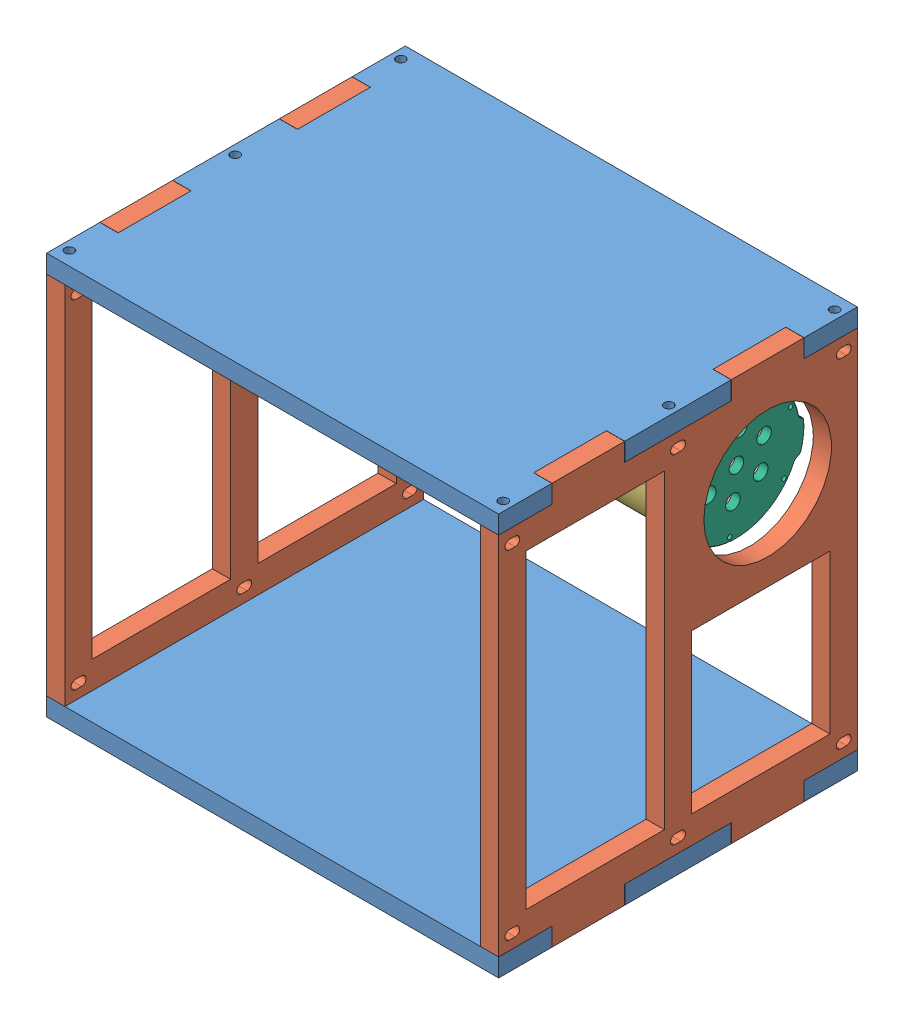
SolidWorks assembly EnsamblajeRobotC_Movimiento, configuration Predeterminado. Lengths in mm.
Overall size (315 280 250).
10 component instances, 6 part files, 10 mates.
Components (placement in the parent):
- TP_Base-1: TP_Base [Predeterminado] at origin size (315 12.7 250)
- Side_Base-1: Side_Base [Predeterminado] at (-157.5 -127.3 0) x (0 0 -1) z (1 0 0) size (250 280 12.7)
- Side_Base-2: Side_Base [Predeterminado] at (144.8 -127.3 0) x (0 0 -1) z (1 0 0) size (250 280 12.7)
- EnsambleTubo-1: EnsambleTubo [Predeterminado] at (123.7041 -62.5 -62.5) x (1 0 0) z (0 0.011715 0.999931) size (292.35 100.44 103.58)
  - WTE3-P-LOCKING-TUBE-240-R2-1: WTE3-P-LOCKING-TUBE-240-R2 [Predeterminado] at origin size (240.01 88.9 88.9)
  - WTE3-M-LOCKING-FLANGE-SEAL-R1-RP-1: WTE3-M-LOCKING-FLANGE-SEAL-R1-RP [Predeterminado] at (-21 0 0) x (0 0 -1) z (1 0 0) size (88.9 95.83 27.56)
  - WTE3-M-LOCKING-FLANGE-SEAL-R1-RP-2: WTE3-M-LOCKING-FLANGE-SEAL-R1-RP [Predeterminado] at (-219 0 0) x (0 0 1) z (-1 0 0) size (88.9 95.83 27.56)
  - WTE3-P-DOME-R1-1: WTE3-P-DOME-R1 [Default] at (-246 0 0) x (0 0.996902 0.078658) z (0 -0.078658 0.996902) size (79.25 34.35 79.25)
  - WTE3-M-END-CAP-7-HOLE-R1-1: WTE3-M-END-CAP-7-HOLE-R1 [Default] at (6 0 0) x (0 -0.102065 -0.994778) z (1 0 0) size (95 88.9 6)
- TP_Base-2: TP_Base [Predeterminado] at (0 -267.3 0) size (315 12.7 250)
Mates (geometry in assembly coordinates):
- Coincidente1: coincident anti-aligned: plane of TP_Base-1 through (-144.8 0 87.9) normal (-1 0 0); plane of Side_Base-1 through (-144.8 -127.3 0) normal (1 0 0)
- Coincidente2: coincident anti-aligned: plane of TP_Base-1 through (0 0 0) normal (0 -1 0); plane of Side_Base-1 through (-157.5 0 125) normal (0 1 0)
- Coincidente3: coincident aligned: plane of TP_Base-1 through (-157.5 12.7 125) normal (0 0 1); plane of Side_Base-1 through (-144.8 -267.3 125) normal (0 0 1)
- Coincidente4: coincident anti-aligned: plane of TP_Base-1 through (0 0 0) normal (0 -1 0); plane of Side_Base-2 through (144.8 0 125) normal (0 1 0)
- Coincidente5: coincident anti-aligned: plane of TP_Base-1 through (144.8 0 87.9) normal (1 0 0); plane of Side_Base-2 through (144.8 -127.3 0) normal (-1 0 0)
- Coincidente6: coincident aligned: plane of TP_Base-1 through (-157.5 12.7 125) normal (0 0 1); plane of Side_Base-2 through (157.5 -267.3 125) normal (0 0 1)
- Coincidente7: coincident anti-aligned: plane of Side_Base-1 through (-157.5 -254.6 125) normal (0 -1 0); plane of TP_Base-2 through (0 -254.6 0) normal (0 1 0)
- Coincidente8: coincident aligned: plane of Side_Base-1 through (-144.8 -267.3 125) normal (0 0 1); plane of TP_Base-2 through (-157.5 -254.6 125) normal (0 0 1)
- Coincidente9: coincident aligned: plane of Side_Base-1 through (-157.5 -127.3 0) normal (-1 0 0); plane of TP_Base-2 through (-157.5 -254.6 125) normal (-1 0 0)
- Concéntrica1: concentric aligned: circle of Side_Base-2; circle of EnsambleTubo-1/WTE3-M-END-CAP-7-HOLE-R1-1
